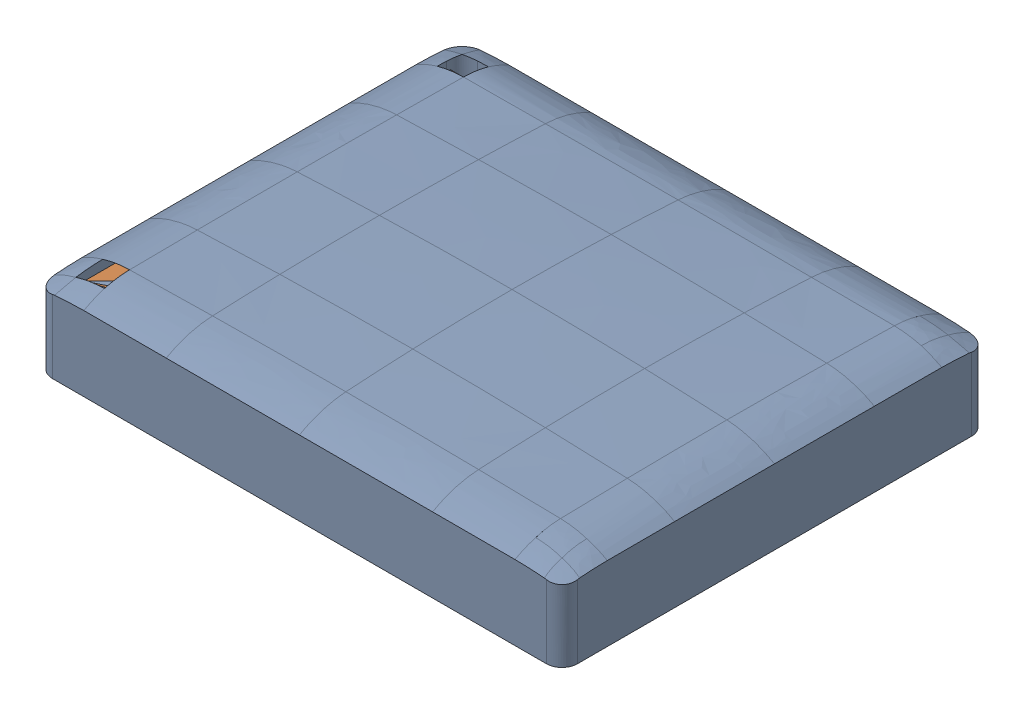
SolidWorks assembly Contiusholeleftout, configuration 默认. Lengths in mm.
Overall size (23.8 4.28 19.29).
2 component instances, 2 part files, 5 mates.
Components (placement in the parent):
- 3Con1612611UP-1: 3Con1612611UP [默认] at origin size (23.8 4.28 19.29)
- continuous-1: continuous [默认] at (-9.5635 21.2 7.9622) x (1 0 0) z (0 1 0) size (19.5 16.5 0.4)
Mates (geometry in assembly coordinates):
- 重合2: coordinate: point of 3Con1612611UP-1
- 平行1: parallel aligned: plane of 3Con1612611UP-1 through (-11.375 18.2 -9.375) normal (0 -1 0); plane of continuous-1 through (-9.5635 21.2 7.9622) normal (0 -1 0)
- 平行2: parallel: plane of 3Con1612611UP-1 through (11.575 22 8.375) normal (1 0 0); line of continuous-1 through (8.4365 21.6 7.9622) axis (0 0 -1)
- 平行3: parallel aligned: plane of 3Con1612611UP-1 through (-0.25 22 9.075) normal (0 0 1); plane of continuous-1 through (-9.5635 21.6 7.9622) normal (0 0 1)
- 距离1: distance = 3 mm aligned: plane of continuous-1 through (-9.5635 21.2 7.9622) normal (0 -1 0); plane of 3Con1612611UP-1 through (-11.375 18.2 -9.375) normal (0 -1 0)
